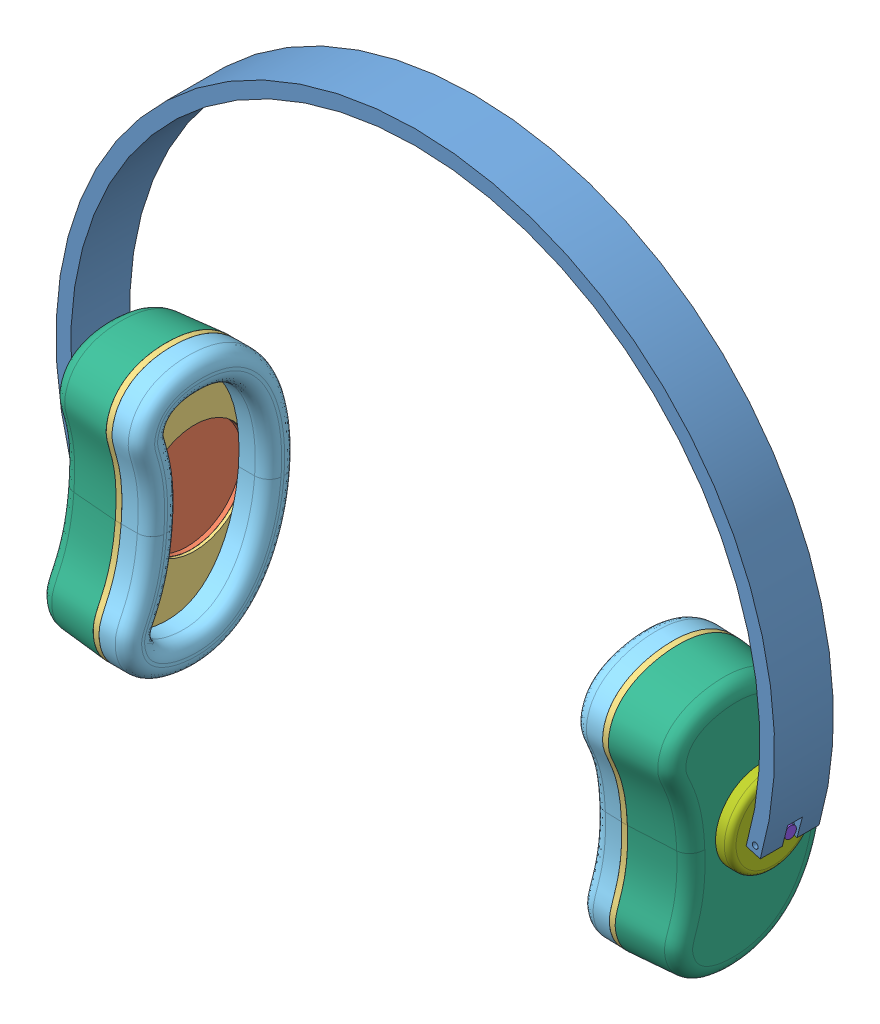
SolidWorks assembly assambly koptelefoon, configuration Default. Lengths in mm.
Overall size (244.38 205.13 72.43).
17 component instances, 8 part files, 6 mates.
Components (placement in the parent):
- band-1: band [Default] at (-2.4357 89.8441 210.46) size (244.38 156.4 20)
- assambly speaker-1: assambly speaker [Default] at (95.3286 -19.2059 224.3949) x (-0.035654 -0.998788 -0.033941) z (-0.999363 0.035675 0) size (101.14 69.03 42.89)
  - speakertje-1: speakertje [Default] at (38.7 -2.6228 10.2754) x (0 1 0) z (-1 0 0) size (38.7 4.9 38.7)
  - speaker houder-1: speaker houder [Default] at (37.6436 -27.6005 9.2754) x (0.042255 0.999107 0) z (0 0 1) size (56.7 91.78 17)
  - speaker houder binnenkant-1: speaker houder binnenkant [Default] at (38.8382 0.6437 22.4754) x (0.042255 0.999107 0) z (0 0 -1) size (42.77 77.51 6.81)
  - mooi kussentje-3: mooi kussentje [Default] at (38.6015 -3.0858 11.2754) x (0.042255 0.999107 0) z (0 0 1) size (64.93 98.49 10.39)
  - speaker houder kap-3: speaker houder kap [Default] at (38.8382 0.6437 9.2754) x (0.042255 0.999107 0) z (0 0 -1) size (63.1 97.32 20.59)
  - draaischijfhouder-1: draaischijfhouder [Default] at (38.7 -2.6228 -10.7246) x (-1 0 0) z (0 -1 0) size (30 5 30)
  - draaischijf-2: draaischijf [Default] at (38.7 -2.6228 -11.2246) x (0.033941 -0.999424 0) z (0.999424 0.033941 0) size (16 10 16)
- assambly speaker-2: assambly speaker [Default] at (-98.8717 -97.0747 224.3949) x (0.001568 0.999423 -0.033941) z (0.999999 -0.001569 0) size (101.14 69.03 42.89)
  - speakertje-1: speakertje [Default] at (38.7 -2.6228 10.2754) x (0 1 0) z (-1 0 0) size (38.7 4.9 38.7)
  - speaker houder-1: speaker houder [Default] at (37.6436 -27.6005 9.2754) x (0.042255 0.999107 0) z (0 0 1) size (56.7 91.78 17)
  - speaker houder binnenkant-1: speaker houder binnenkant [Default] at (38.8382 0.6437 22.4754) x (0.042255 0.999107 0) z (0 0 -1) size (42.77 77.51 6.81)
  - mooi kussentje-3: mooi kussentje [Default] at (38.6015 -3.0858 11.2754) x (0.042255 0.999107 0) z (0 0 1) size (64.93 98.49 10.39)
  - speaker houder kap-3: speaker houder kap [Default] at (38.8382 0.6437 9.2754) x (0.042255 0.999107 0) z (0 0 -1) size (63.1 97.32 20.59)
  - draaischijfhouder-1: draaischijfhouder [Default] at (38.7 -2.6228 -10.7246) x (-1 0 0) z (0 -1 0) size (30 5 30)
  - draaischijf-2: draaischijf [Default] at (38.7 -2.6228 -11.2246) x (0.033941 -0.999424 0) z (0.999424 0.033941 0) size (16 10 16)
Mates (geometry in assembly coordinates):
- Concentric1: concentric anti-aligned: cylinder of band-1 through (113.1643 -58.4559 210.46) axis (0 0 1) radius 1; cylinder of assambly speaker-1/draaischijf-2 through (113.1643 -58.4559 228.46) axis (0 0 -1) radius 1
- Distance1: distance = 10 mm: point of assambly speaker-1/draaischijf-2; plane of band-1 through (-2.4357 -27.3434 230.46) normal (0 0 1)
- Concentric2: concentric anti-aligned: cylinder of band-1 through (-118.0357 -58.4559 210.46) axis (0 0 1) radius 1; cylinder of assambly speaker-2/draaischijf-2 through (-118.0357 -58.4559 228.46) axis (0 0 -1) radius 1
- Distance2: distance = 10 mm: point of assambly speaker-2/draaischijf-2; plane of band-1 through (-2.4357 -27.3434 210.46) normal (0 0 -1)
- LimitAngle3: limit planar angle = 4.427026 rad aligned: plane of band-1 through (-119.7357 -61.5559 230.46) normal (0.28 -0.96 0); plane of assambly speaker-2/speaker houder kap-3 through (-109.4685 -15.6264 214.7437) normal (-0.999999 0.001569 0)
- LimitAngle4: limit planar angle = 1.818908 rad aligned: plane of assambly speaker-1/speaker houder kap-3 through (103.1413 -100.9683 214.7437) normal (0.999363 -0.035675 0); plane of band-1 through (110.0643 -60.1559 230.46) normal (-0.28 -0.96 0)
